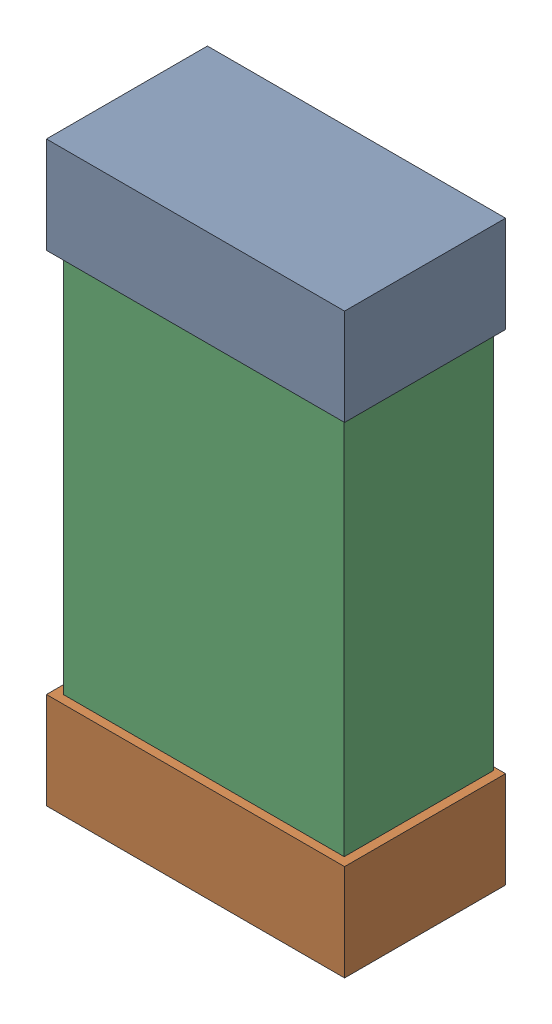
SolidWorks assembly R43, configuration Default. Lengths in mm.
Overall size (0.85 1.65 0.46).
6 component instances, 2 part files, 0 mates.
Components (placement in the parent):
- 432138512_18-1: 432138512_18 [Default] at (43.5001 5.1291 -0.8715) size (0.85 0.28 0.46)
  - Extruded-1: Extruded [Default] at origin size (0.85 0.28 0.46)
- 432138512_19-1: 432138512_19 [Default] at (43.5001 3.7576 -0.8715) size (0.85 0.28 0.46)
  - Extruded-1: Extruded [Default] at origin size (0.85 0.28 0.46)
- 432124816_9-1: 432124816_9 [Default] at (43.5001 4.4434 -0.8615) size (0.8 1.5 0.42)
  - Extruded (1)-1: Extruded (1) [Default] at origin size (0.8 1.5 0.42)
